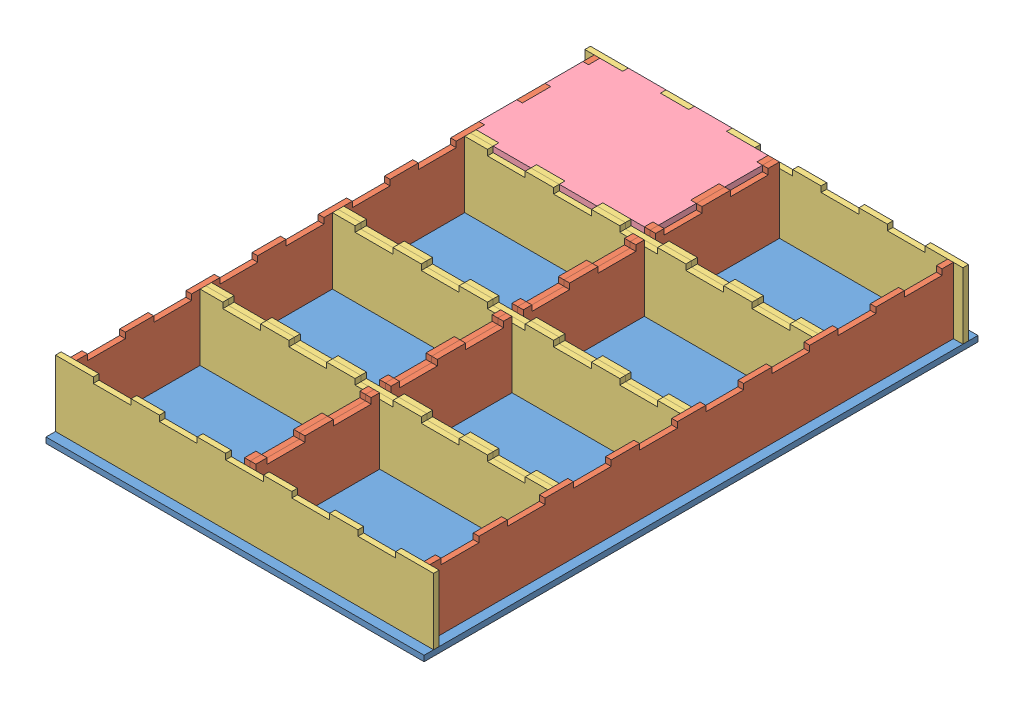
SolidWorks assembly Assem1, configuration Default. Lengths in mm.
Overall size (200 38 293).
20 component instances, 4 part files, 57 mates.
Components (placement in the parent):
- base-1: base [Default] at (16.4212 149.2181 390.9951) size (200 3 293)
- long_side-1: long_side [Default] at (21.4212 152.2181 382.9951) size (3 38 277)
- side-1: side [Default] at (16.4212 152.2181 102.9951) x (1 0 0) z (0 0 -1) size (200 38 3)
- long_side-2: long_side [Default] at (208.4212 152.2181 382.9951) size (3 38 277)
- side-2: side [Default] at (16.4212 152.2181 382.9951) x (1 0 0) z (0 0 -1) size (200 38 3)
- side-3: side [inside] at (208.4212 152.2181 177.4951) x (-1 0 0) z (0 0 1) size (184 38 3)
- side-4: side [inside] at (208.4212 152.2181 174.4951) x (-1 0 0) z (0 0 1) size (184 38 3)
- side-5: side [inside] at (208.4212 152.2181 314.4951) x (-1 0 0) z (0 0 1) size (184 38 3)
- side-6: side [inside] at (208.4212 152.2181 244.4951) x (-1 0 0) z (0 0 1) size (184 38 3)
- side-7: side [inside] at (24.4212 152.2181 244.4951) x (1 0 0) z (0 0 -1) size (184 38 3)
- side-8: side [inside] at (208.4212 152.2181 317.4951) x (-1 0 0) z (0 0 1) size (184 38 3)
- long_side-3: long_side [inside] at (113.4212 152.2181 382.9951) size (3 38 65.5)
- long_side-5: long_side [inside_middle] at (116.4212 152.2181 177.4951) x (-1 0 0) z (0 0 -1) size (3 38 64)
- long_side-7: long_side [inside_middle] at (116.4212 152.2181 241.4951) size (3 38 64)
- long_side-8: long_side [inside_middle] at (116.4212 152.2181 311.4951) size (3 38 64)
- long_side-9: long_side [inside_middle] at (113.4212 152.2181 311.4951) size (3 38 64)
- long_side-10: long_side [inside] at (116.4212 152.2181 382.9951) size (3 38 65.5)
- long_side-11: long_side [inside] at (116.4212 152.2181 105.9951) x (-1 0 0) z (0 0 -1) size (3 38 65.5)
- long_side-12: long_side [inside] at (119.4212 152.2181 105.9951) x (-1 0 0) z (0 0 -1) size (3 38 65.5)
- top-1: top [Default] at (24.4212 184.2181 171.4951) size (95 3 71.5)
Mates (geometry in assembly coordinates):
- Coincident2: coincident anti-aligned: plane of base-1 through (156.4212 142.2181 102.9951) normal (0 0 1); plane of side-1 through (16.4212 152.2181 102.9951) normal (0 0 -1)
- Coincident3: coincident aligned: plane of base-1 through (216.4212 152.2181 390.9951) normal (1 0 0); plane of side-1 through (216.4212 152.2181 105.9951) normal (1 0 0)
- Coincident4: coincident anti-aligned: plane of base-1 through (16.4212 152.2181 390.9951) normal (0 1 0); plane of side-1 through (196.4212 152.2181 105.9951) normal (0 -1 0)
- Coincident5: coincident anti-aligned: plane of base-1 through (24.4212 142.2181 460.9951) normal (-1 0 0); plane of long_side-1 through (24.4212 152.2181 382.9951) normal (1 0 0)
- Coincident6: coincident anti-aligned: plane of long_side-1 through (24.4212 152.2181 105.9951) normal (0 0 -1); plane of side-1 through (16.4212 152.2181 105.9951) normal (0 0 1)
- Coincident7: coincident aligned: plane of base-1 through (16.4212 149.2181 390.9951) normal (0 -1 0); plane of long_side-1 through (24.4212 149.2181 376.9951) normal (0 -1 0)
- Coincident9: coincident aligned: plane of base-1 through (216.4212 152.2181 390.9951) normal (1 0 0); plane of side-2 through (216.4212 152.2181 385.9951) normal (1 0 0)
- Coincident11: coincident aligned: plane of base-1 through (16.4212 149.2181 390.9951) normal (0 -1 0); plane of side-2 through (71.4212 149.2181 385.9951) normal (0 -1 0)
- Coincident14: coincident aligned: plane of base-1 through (16.4212 149.2181 390.9951) normal (0 -1 0); plane of long_side-2 through (211.4212 149.2181 131.9951) normal (0 -1 0)
- Coincident15: coincident anti-aligned: plane of side-1 through (16.4212 152.2181 105.9951) normal (0 0 1); plane of long_side-2 through (211.4212 152.2181 105.9951) normal (0 0 -1)
- Coincident16: coincident anti-aligned: plane of base-1 through (211.4212 142.2181 600.9951) normal (-1 0 0); plane of long_side-2 through (211.4212 152.2181 382.9951) normal (1 0 0)
- Coincident17: coincident anti-aligned: plane of base-1 through (16.4212 152.2181 390.9951) normal (0 1 0); plane of side-3 through (106.4212 152.2181 174.4951) normal (0 -1 0)
- Coincident18: coincident anti-aligned: plane of long_side-2 through (208.4212 152.2181 382.9951) normal (-1 0 0); plane of side-3 through (208.4212 152.2181 174.4951) normal (1 0 0)
- Coincident19: coincident anti-aligned: plane of base-1 through (36.4212 142.2181 177.4951) normal (0 0 -1); plane of side-3 through (208.4212 152.2181 177.4951) normal (0 0 1)
- Coincident20: coincident anti-aligned: plane of base-1 through (16.4212 152.2181 390.9951) normal (0 1 0); plane of side-4 through (208.4212 152.2181 171.4951) normal (0 -1 0)
- Coincident21: coincident anti-aligned: plane of side-3 through (208.4212 152.2181 174.4951) normal (0 0 -1); plane of side-4 through (208.4212 152.2181 174.4951) normal (0 0 1)
- Coincident22: coincident aligned: plane of side-3 through (106.4212 187.2181 174.4951) normal (0 1 0); plane of side-4 through (208.4212 187.2181 171.4951) normal (0 1 0)
- Coincident23: coincident anti-aligned: plane of long_side-2 through (208.4212 152.2181 382.9951) normal (-1 0 0); plane of side-4 through (208.4212 152.2181 171.4951) normal (1 0 0)
- Coincident24: coincident anti-aligned: plane of base-1 through (141.4212 142.2181 247.4951) normal (0 0 -1); plane of side-7 through (24.4212 152.2181 247.4951) normal (0 0 1)
- Coincident25: coincident anti-aligned: plane of base-1 through (16.4212 152.2181 390.9951) normal (0 1 0); plane of side-7 through (91.4212 152.2181 247.4951) normal (0 -1 0)
- Coincident26: coincident anti-aligned: plane of long_side-1 through (24.4212 152.2181 382.9951) normal (1 0 0); plane of side-7 through (24.4212 152.2181 247.4951) normal (-1 0 0)
- Coincident27: coincident aligned: plane of base-1 through (16.4212 149.2181 390.9951) normal (0 -1 0); plane of side-6 through (196.4212 149.2181 241.4951) normal (0 -1 0)
- Coincident28: coincident anti-aligned: plane of side-6 through (208.4212 152.2181 244.4951) normal (0 0 1); plane of side-7 through (24.4212 152.2181 244.4951) normal (0 0 -1)
- Coincident29: coincident anti-aligned: plane of long_side-2 through (208.4212 152.2181 382.9951) normal (-1 0 0); plane of side-6 through (208.4212 152.2181 241.4951) normal (1 0 0)
- Coincident30: coincident anti-aligned: plane of base-1 through (16.4212 152.2181 390.9951) normal (0 1 0); plane of side-5 through (176.4212 152.2181 311.4951) normal (0 -1 0)
- Coincident31: coincident anti-aligned: plane of long_side-2 through (208.4212 152.2181 382.9951) normal (-1 0 0); plane of side-5 through (208.4212 152.2181 311.4951) normal (1 0 0)
- Coincident32: coincident anti-aligned: plane of base-1 through (141.4212 142.2181 311.4951) normal (0 0 1); plane of side-5 through (208.4212 152.2181 311.4951) normal (0 0 -1)
- Coincident33: coincident anti-aligned: plane of base-1 through (16.4212 152.2181 390.9951) normal (0 1 0); plane of side-8 through (141.4212 152.2181 314.4951) normal (0 -1 0)
- Coincident34: coincident anti-aligned: plane of long_side-2 through (208.4212 152.2181 382.9951) normal (-1 0 0); plane of side-8 through (208.4212 152.2181 314.4951) normal (1 0 0)
- Coincident35: coincident anti-aligned: plane of side-5 through (208.4212 152.2181 314.4951) normal (0 0 1); plane of side-8 through (208.4212 152.2181 314.4951) normal (0 0 -1)
- Coincident37: coincident anti-aligned: plane of base-1 through (119.4212 142.2181 286.9951) normal (-1 0 0); plane of long_side-8 through (119.4212 152.2181 311.4951) normal (1 0 0)
- Coincident38: coincident anti-aligned: plane of side-7 through (24.4212 152.2181 247.4951) normal (0 0 1); plane of long_side-8 through (109.4212 192.2181 247.4951) normal (0 0 -1)
- Coincident39: coincident aligned: plane of base-1 through (16.4212 149.2181 390.9951) normal (0 -1 0); plane of long_side-8 through (119.4212 149.2181 271.9951) normal (0 -1 0)
- Coincident40: coincident anti-aligned: plane of long_side-7 through (119.4212 152.2181 241.4951) normal (1 0 0); plane of base-1 through (119.4212 142.2181 216.9951) normal (-1 0 0)
- Coincident41: coincident anti-aligned: plane of side-3 through (208.4212 152.2181 177.4951) normal (0 0 1); plane of long_side-7 through (109.4212 192.2181 177.4951) normal (0 0 -1)
- Coincident42: coincident aligned: plane of long_side-7 through (119.4212 187.2181 216.9951) normal (0 1 0); plane of long_side-8 through (119.4212 187.2181 286.9951) normal (0 1 0)
- Coincident43: coincident anti-aligned: plane of base-1 through (113.4212 142.2181 216.9951) normal (1 0 0); plane of long_side-9 through (113.4212 152.2181 311.4951) normal (-1 0 0)
- Coincident45: coincident aligned: plane of long_side-8 through (119.4212 184.2181 306.9951) normal (0 1 0); plane of long_side-9 through (116.4212 184.2181 306.9951) normal (0 1 0)
- Coincident46: coincident anti-aligned: plane of side-5 through (208.4212 152.2181 311.4951) normal (0 0 -1); plane of long_side-9 through (116.4212 152.2181 311.4951) normal (0 0 1)
- Coincident47: coincident anti-aligned: plane of long_side-5 through (116.4212 152.2181 177.4951) normal (1 0 0); plane of long_side-7 through (116.4212 152.2181 241.4951) normal (-1 0 0)
- Coincident48: coincident anti-aligned: plane of side-6 through (208.4212 152.2181 241.4951) normal (0 0 -1); plane of long_side-5 through (123.4212 192.2181 241.4951) normal (0 0 1)
- Coincident49: coincident aligned: plane of long_side-5 through (113.4212 187.2181 201.9951) normal (0 1 0); plane of long_side-7 through (119.4212 187.2181 216.9951) normal (0 1 0)
- Coincident50: coincident anti-aligned: plane of base-1 through (119.4212 142.2181 321.9951) normal (-1 0 0); plane of long_side-10 through (119.4212 152.2181 382.9951) normal (1 0 0)
- Coincident51: coincident aligned: plane of long_side-9 through (116.4212 187.2181 286.9951) normal (0 1 0); plane of long_side-10 through (119.4212 187.2181 356.9951) normal (0 1 0)
- Coincident52: coincident anti-aligned: plane of side-8 through (208.4212 152.2181 317.4951) normal (0 0 1); plane of long_side-10 through (109.4212 192.2181 317.4951) normal (0 0 -1)
- Coincident53: coincident anti-aligned: plane of long_side-3 through (116.4212 152.2181 382.9951) normal (1 0 0); plane of long_side-10 through (116.4212 152.2181 382.9951) normal (-1 0 0)
- Coincident54: coincident aligned: plane of long_side-3 through (116.4212 187.2181 356.9951) normal (0 1 0); plane of long_side-10 through (119.4212 187.2181 356.9951) normal (0 1 0)
- Coincident55: coincident: plane of side-8 through (208.4212 152.2181 317.4951) normal (0 0 1); moEndPointRef_w of long_side-3
- Coincident56: coincident anti-aligned: plane of base-1 through (113.4212 142.2181 111.9951) normal (1 0 0); plane of long_side-11 through (113.4212 152.2181 105.9951) normal (-1 0 0)
- Coincident57: coincident anti-aligned: plane of side-4 through (208.4212 152.2181 171.4951) normal (0 0 -1); plane of long_side-11 through (123.4212 192.2181 171.4951) normal (0 0 1)
- Coincident58: coincident: line of long_side-5 through (116.4212 187.2181 201.9951) axis (0 0 1); plane of long_side-11 through (113.4212 187.2181 131.9951) normal (0 1 0)
- Coincident59: coincident anti-aligned: plane of side-1 through (16.4212 152.2181 105.9951) normal (0 0 1); plane of long_side-12 through (116.4212 152.2181 105.9951) normal (0 0 -1)
- Coincident60: coincident aligned: plane of long_side-11 through (113.4212 187.2181 131.9951) normal (0 1 0); plane of long_side-12 through (116.4212 187.2181 131.9951) normal (0 1 0)
- Coincident61: coincident anti-aligned: plane of long_side-11 through (116.4212 152.2181 105.9951) normal (1 0 0); plane of long_side-12 through (116.4212 152.2181 105.9951) normal (-1 0 0)
- Coincident62: coincident aligned: plane of side-4 through (71.4212 187.2181 171.4951) normal (0 1 0); plane of top-1 through (24.4212 187.2181 168.4951) normal (0 1 0)
- Coincident63: coincident aligned: plane of long_side-1 through (21.4212 152.2181 382.9951) normal (-1 0 0); plane of top-1 through (21.4212 187.2181 108.9951) normal (-1 0 0)
- Coincident64: coincident aligned: plane of side-1 through (16.4212 152.2181 102.9951) normal (0 0 -1); plane of top-1 through (71.4212 187.2181 102.9951) normal (0 0 -1)
